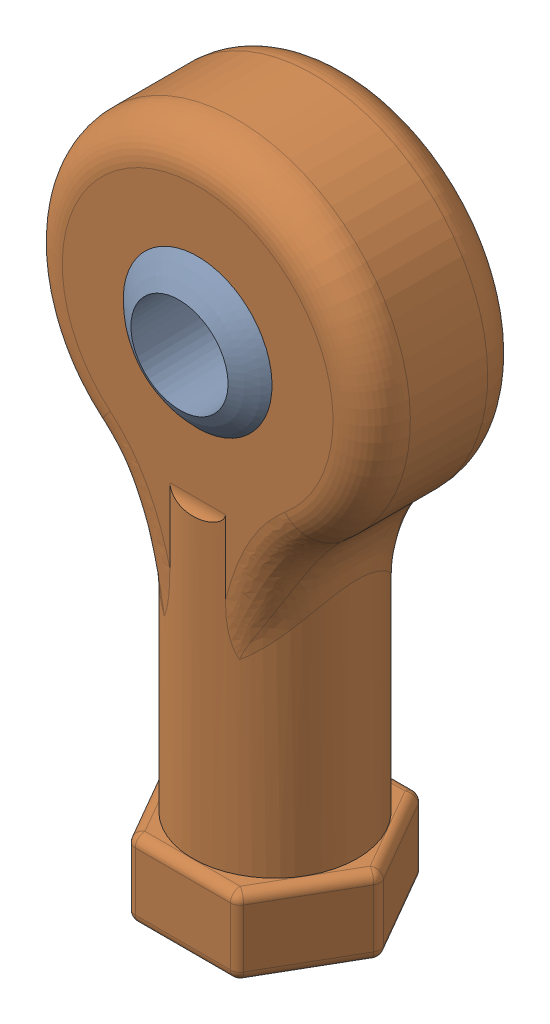
SolidWorks assembly Female Heim Joint, configuration Default. Lengths in mm.
Overall size (18 36 10.15).
2 component instances, 2 part files, 1 mates.
Components (placement in the parent):
- Hiem Joint Bearing-1: Hiem Joint Bearing [Default] at (-2.0555 0.0438 1.0549) x (0.999985 0.003631 -0.004027) z (0.004086 -0.016306 0.999859) size (11.11 11.11 9.92)
- Hiem Joint Socket-1: Hiem Joint Socket [M5] at (-2.0555 0.0438 1.0549) x (1 0 0) z (0 -1 0) size (18 9.53 36)
Mates (geometry in assembly coordinates):
- Concentric1: concentric: sphere of Ball-1; sphere of Female Hiem Joint-1
